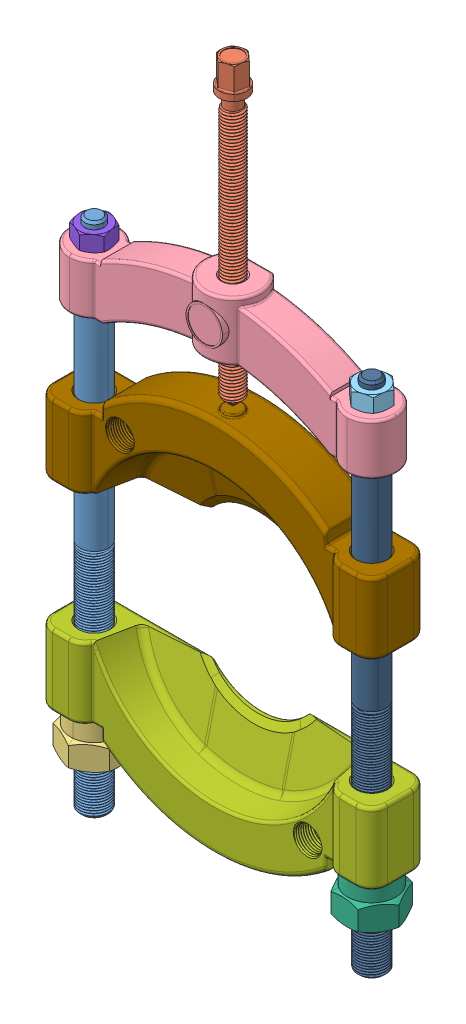
SolidWorks assembly ENSAMBLE 1, configuration Predeterminado. Lengths in mm.
Overall size (218.01 452 51.61).
10 component instances, 10 part files, 20 mates.
Components (placement in the parent):
- Sólido1-1: Sólido1 [Predeterminado] at (-84.4757 -14.3556 -86.9303) x (0.028636 0 -0.99959) z (0.99959 0 0.028636) size (18.01 322.07 18.01)
- Sólido2-1: Sólido2 [Predeterminado] at (0 7.6376 0) x (0.659771 0 -0.751467) z (0.751467 0 0.659771) size (36.57 206.07 36.57)
- Sólido3-1: Sólido3 [Predeterminado] at (-0.5719 0 -9.957) x (0.993424 0 -0.114493) z (0.114493 0 0.993424) size (36.97 27 36.96)
- Sólido4-1: Sólido4 [Predeterminado] at (0 -14.3556 0) size (204.92 57.01 33.51)
- Sólido5-1: Sólido5 [Predeterminado] at (29.7707 -14.3556 65.5117) x (0.657674 0 -0.753303) z (0.753303 0 0.657674) size (19.01 10.01 21.94)
- Sólido6-1: Sólido6 [Predeterminado] at (14.8565 0 -48.6139) x (0.829168 0 0.558999) z (-0.558999 0 0.829168) size (32.01 27 36.96)
- Sólido7-1: Sólido7 [Predeterminado] at origin size (210 80.07 36.08)
- Sólido8-1: Sólido8 [Predeterminado] at (-1.0044 -14.3556 -13.1788) x (0.988451 0 -0.15154) z (0.15154 0 0.988451) size (21.94 10.01 21.94)
- Sólido9-1: Sólido9 [Predeterminado] at (0 5.6508 0) size (210 80.07 36.08)
- Sólido10-1: Sólido10 [Predeterminado] at (125.5437 -14.3556 -77.9413) x (-0.443596 0 0.896227) z (-0.896227 0 -0.443596) size (18.01 322.07 18.01)
Mates (geometry in assembly coordinates):
- Concéntrica1: concentric anti-aligned: cylinder of Sólido4-1 through (-86.966 21.185 0) axis (0 1 0) radius 9; cylinder of Sólido9-1 through (-86.966 -49.9254 0) axis (0 -1 0) radius 9
- Concéntrica2: concentric anti-aligned: cylinder of Sólido1-1 through (-86.966 92.7164 0) axis (0 -1 0) radius 9; cylinder of Sólido7-1 through (-86.966 -205.0686 0) axis (0 1 0) radius 9
- Concéntrica3: concentric anti-aligned: cylinder of Sólido7-1 through (86.966 -205.0686 0) axis (0 1 0) radius 9; cylinder of Sólido10-1 through (86.966 92.7164 0) axis (0 -1 0) radius 9
- Concéntrica4: concentric anti-aligned: cylinder of Sólido6-1 through (86.966 -183.3536 0) axis (0 1 0) radius 9; cylinder of Sólido10-1 through (86.966 92.7164 0) axis (0 -1 0) radius 9
- Concéntrica5: concentric anti-aligned: cylinder of Sólido1-1 through (-86.966 92.7164 0) axis (0 -1 0) radius 9; cylinder of Sólido3-1 through (-86.966 -183.3536 0) axis (0 1 0) radius 9
- Coincidente1: coincident anti-aligned: plane of Sólido3-1 through (-86.966 -172.3554 0) normal (0 1 0); plane of Sólido7-1 through (0 -172.3554 -18.034) normal (0 -1 0)
- Coincidente2: coincident anti-aligned: plane of Sólido6-1 through (86.966 -172.3554 0) normal (0 1 0); plane of Sólido7-1 through (0 -172.3554 -18.034) normal (0 -1 0)
- Concéntrica8: concentric aligned: cylinder of Sólido9-1 through (86.966 -49.9254 0) axis (0 -1 0) radius 9; cylinder of Sólido10-1 through (86.966 92.7164 0) axis (0 -1 0) radius 9
- Concéntrica9: concentric aligned: cylinder of Sólido1-1 through (-86.966 92.7164 0) axis (0 -1 0) radius 9; cylinder of Sólido9-1 through (-86.966 -49.9254 0) axis (0 -1 0) radius 9
- Distancia4: distance = 80 mm anti-aligned: plane of Sólido7-1 through (-75.1332 -127.497 13.0302) normal (0 1 0); plane of Sólido9-1 through (-75.1332 -47.497 13.0302) normal (0 -1 0)
- Concéntrica10: concentric aligned: cylinder of Sólido4-1 through (86.966 21.185 0) axis (0 1 0) radius 9; cylinder of Sólido10-1 through (86.966 21.185 0) axis (0 1 0) radius 5.9944
- Distancia1: distance = 30 mm aligned: plane of Sólido1-1 through (-86.966 -229.3556 0) normal (0 -1 0); plane of Sólido3-1 through (-0.5719 -199.3556 -9.957) normal (0 -1 0)
- Distancia2: distance = 30 mm aligned: plane of Sólido6-1 through (14.8565 -199.3556 -48.6139) normal (0 -1 0); plane of Sólido10-1 through (86.966 -229.3556 0) normal (0 -1 0)
- Concéntrica11: concentric anti-aligned: cylinder of Sólido5-1 through (86.966 88.6524 0) axis (0 -1 0) radius 4.4944; cylinder of Sólido10-1 through (86.966 21.185 0) axis (0 1 0) radius 5.9944
- Concéntrica12: concentric anti-aligned: cylinder of Sólido1-1 through (-86.966 21.185 0) axis (0 1 0) radius 5.9944; cylinder of Sólido8-1 through (-86.966 88.6524 0) axis (0 -1 0) radius 4.4944
- Concéntrica13: concentric anti-aligned: cylinder of Sólido2-1 through (0 222.6376 0) axis (0 1 0) radius 5.1716; cylinder of Sólido4-1 through (0 103.6384 0) axis (0 -1 0) radius 6.35
- Distancia3: distance = 100 mm anti-aligned: plane of Sólido2-1 through (0 203.6384 0) normal (0 -1 0); plane of Sólido4-1 through (0 103.6384 0) normal (0 1 0)
- Coincidente8: coincident anti-aligned: plane of Sólido4-1 through (0 46.6408 10.9982) normal (0 -1 0); plane of Sólido10-1 through (125.5437 46.6408 -77.9413) normal (0 1 0)
- Coincidente9: coincident anti-aligned: plane of Sólido4-1 through (0 78.6448 10.9982) normal (0 1 0); plane of Sólido5-1 through (29.7707 78.6448 65.5117) normal (0 -1 0)
- Coincidente10: coincident anti-aligned: plane of Sólido4-1 through (0 78.6448 -18.4775) normal (0 1 0); plane of Sólido8-1 through (-1.0044 78.6448 -13.1788) normal (0 -1 0)
